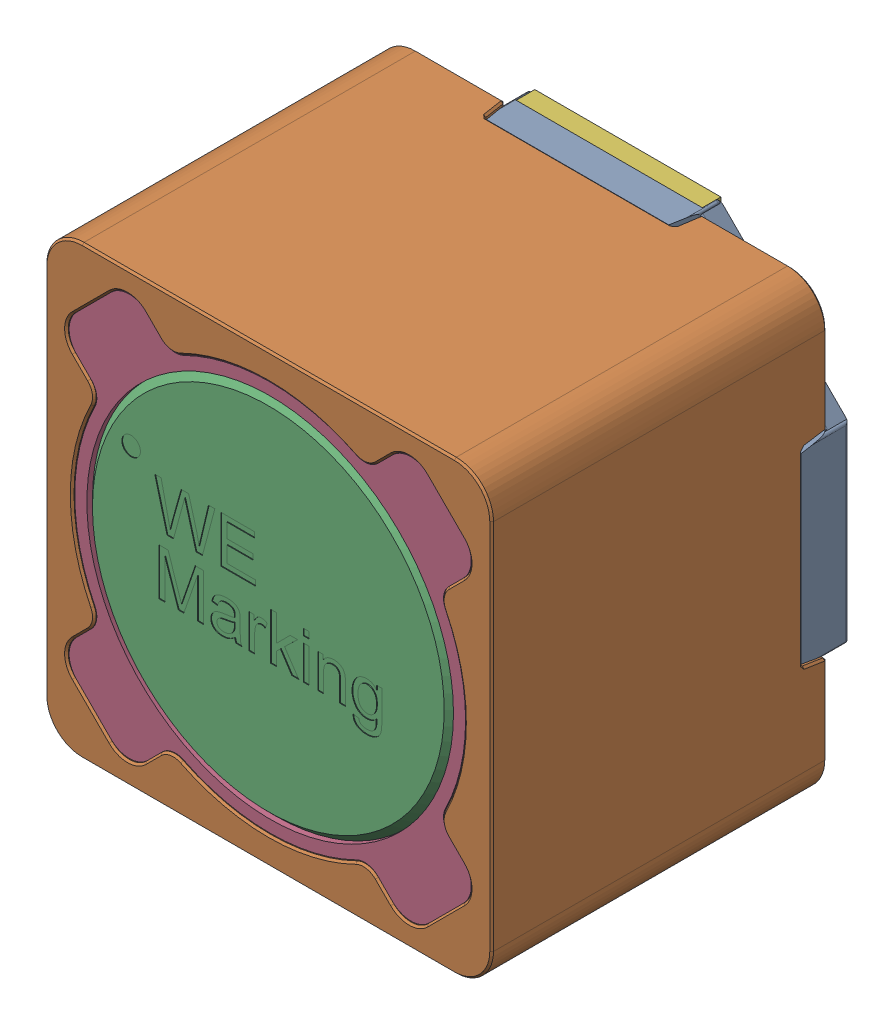
SolidWorks assembly IndPDA_1210, configuration Default. Lengths in mm.
Overall size (12 12 9.66).
11 component instances, 10 part files, 0 mates.
Components (placement in the parent):
- Umspritzung12-12_1-1: Umspritzung12-12_1 [Default] at (0 0 0.94) x (1 0 0) z (0 0 -1) size (12 12 1.3)
- 12x12-9mm-1: 12x12-9mm [Default] at (0 0 9.25) size (12 12 9)
- Core_PD_12x12-9-1: Core_PD_12x12-9 [Default] at (0 0 4.75) size (9.85 9.85 9)
- Glue-1: Glue [Default] at origin size (10.8 10.8 8.9)
- Leadframe_bended-1: Leadframe_bended [Default] at origin size (11.55 12 3.98)
  - Leadframe-1: Leadframe [Default] at origin size (9.3 3.5 0.71)
  - Leadframe_2-1: Leadframe_2 [Default] at origin size (9.3 3.5 0.71)
  - PIN_1-1: PIN_1 [Default] at (-4.2957 4.2957 -5.8993) x (0.5 0.5 -0.707107) z (0.707107 -0.707107 0) size (2.61 2.72 1.6)
  - PIN_2-1: PIN_2 [Default] at (4.2957 4.2957 -5.8993) x (0.5 -0.5 0.707107) z (-0.707107 -0.707107 0) size (2.71 2.61 1.51)
  - PIN_3-1: PIN_3 [Default] at (4.2957 -4.2957 -5.8993) x (0.5 0.5 0.707107) z (-0.707107 0.707107 0) size (2.72 2.61 1.6)
  - PIN_4-1: PIN_4 [Default] at (-4.2957 -4.2957 -5.8993) x (0.5 -0.5 -0.707107) z (0.707107 0.707107 0) size (2.61 2.72 1.6)
